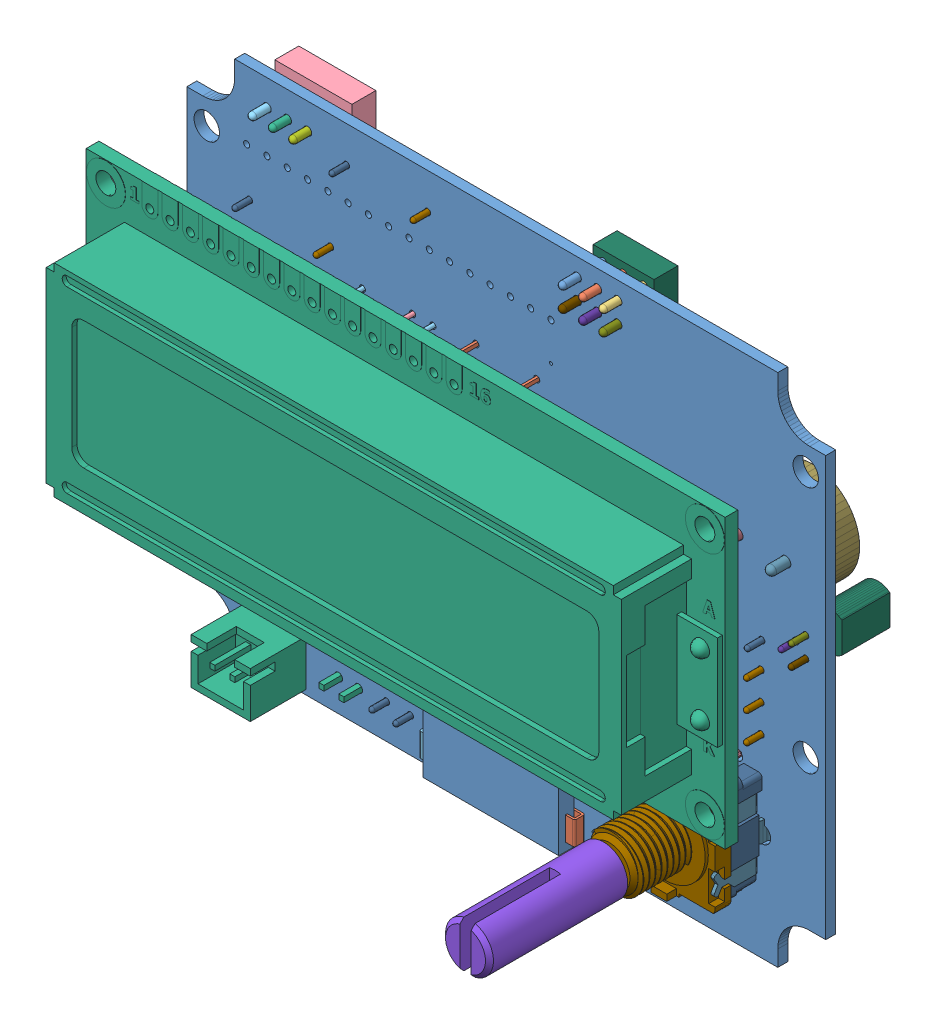
SolidWorks assembly margoulineur2000RevB_2, configuration Défaut. Lengths in mm.
Overall size (81.34 64.5 46.05).
210 component instances, 74 part files, 0 mates.
Components (placement in the parent):
- Layer_1-1: Layer_1 [Défaut] at origin size (80 64.5 1.25)
- U3-1: U3 [Défaut] at (36.2 -50.82 -0.625) x (0 1 0) z (0 0 -1) size (35.56 7.92 7.75)
  - Open CASCADE STEP translator 6.8 1.2.1-1: Open CASCADE STEP translator 6.8 1.2.1 [Défaut] at origin size (35.56 7.92 7.75)
    - Body_1-1: Body_1 [Défaut] at (16.5 3.8 0) x (0 1 0) z (1 0 0) size (7.92 7.75 35.56)
- C7-1: C7 [Défaut] at (28.275 -18.503 -0.625) x (1 0 0) z (0 0 -1) size (4 2 7.75)
  - Open CASCADE STEP translator 6.8 1.3.1-1: Open CASCADE STEP translator 6.8 1.3.1 [Défaut] at origin size (4 2 7.75)
    - Body_1_2-1: Body_1_2 [Défaut] at (1.27 -1.27 0) x (0 1 0) z (0 0 1) size (2 4 4)
    - Pin_1-1: Pin_1 [Défaut] x (0 -1 0) z (0 0 1) size (0.5 0.5 5.5)
    - Pin_2-1: Pin_2 [Défaut] at (2.54 2.54 0) x (0 -1 0) z (0 0 1) size (0.5 0.5 5.5)
- LCD1-1: LCD1 [Défaut] at (77.5 -11 0.625) size (80.25 36 12.9)
  - Open CASCADE STEP translator 6.8 1.4.1-1: Open CASCADE STEP translator 6.8 1.4.1 [Défaut] at origin size (80.25 36 12.9)
    - Body_1_3-1: Body_1_3 [Défaut] at (-37.5 -15.4 11) size (80.25 36 12.9)
- X1-1: X1 [Défaut] at (29.574 -28.08 -0.625) x (0 1 0) z (0 0 -1) size (11 4.5 15.2)
  - Open CASCADE STEP translator 6.8 1.5.1-1: Open CASCADE STEP translator 6.8 1.5.1 [Défaut] at origin size (11 4.5 15.2)
    - Body_1_4-1: Body_1_4 [Défaut] at (2.5 0 0) x (1 0 0) z (0 -1 0) size (11 15.2 4.5)
- C6-1: C6 [Défaut] at (28.267 -32.497 -0.625) x (1 0 0) z (0 0 -1) size (4 2 7.75)
  - Open CASCADE STEP translator 6.8 1.3.1-1: Open CASCADE STEP translator 6.8 1.3.1 [Défaut] at origin size (4 2 7.75)
    - Body_1_2-1: Body_1_2 [Défaut] at (1.27 -1.27 0) x (0 1 0) z (0 0 1) size (2 4 4)
    - Pin_1-1: Pin_1 [Défaut] x (0 -1 0) z (0 0 1) size (0.5 0.5 5.5)
    - Pin_2-1: Pin_2 [Défaut] at (2.54 2.54 0) x (0 -1 0) z (0 0 1) size (0.5 0.5 5.5)
- ENC1-1: ENC1 [Défaut] at (64 -46 0.625) size (13.1 15.13 35.07)
  - Open CASCADE STEP translator 6.8 1.7.1-1: Open CASCADE STEP translator 6.8 1.7.1 [Défaut] at origin size (13.1 15.13 35.07)
    - Body_1-1: Body_1 [Défaut] at (2.5 -6.5 0) x (-1 0 0) z (0 0 1) size (13.1 15.13 35.07)
      - Imported-1: Imported [Défaut] at (0 0 13.6) size (6 6 18)
      - Imported_2-1: Imported_2 [Défaut] at (0 0 3.443) size (11.7 13.8 9.4)
      - Imported_3-1: Imported_3 [Défaut] at (-0.85 -0.6436 6.5892) size (11.7 13.3 3.9)
      - Imported-2: Imported [Défaut] at (0 0 6.6326) size (13.1 14.95 9.45)
        - Imported_2-1: Imported_2 [Défaut] at (-2.5 7.575 -10.2243) x (0 -1 0) z (0 0 1) size (2.34 1.5 6.65)
          - SOLID-1: SOLID [Défaut] at origin size (0.6 1.5 0.15)
          - SOLID_2-1: SOLID_2 [Défaut] at origin size (2.15 1.5 6.65)
        - Imported_2-2: Imported_2 [Défaut] at (0 7.575 -10.2243) x (0 -1 0) z (0 0 1) size (2.34 1.5 6.65)
          - SOLID-1: SOLID [Défaut] at origin size (0.6 1.5 0.15)
          - SOLID_2-1: SOLID_2 [Défaut] at origin size (2.15 1.5 6.65)
        - Imported_2-3: Imported_2 [Défaut] at (2.5 7.575 -10.2243) x (0 -1 0) z (0 0 1) size (2.34 1.5 6.65)
          - SOLID-1: SOLID [Défaut] at origin size (0.6 1.5 0.15)
          - SOLID_2-1: SOLID_2 [Défaut] at origin size (2.15 1.5 6.65)
        - Imported_4-1: Imported_4 [Défaut] at (-2.5 -7.075 -10.2243) x (0 1 0) z (0 0 1) size (2.15 1.5 4.73)
        - Imported_4-2: Imported_4 [Défaut] at (2.5 -7.075 -10.2243) x (0 1 0) z (0 0 1) size (2.15 1.5 4.73)
        - Imported_5-1: Imported_5 [Défaut] at (-24.7094 3.8245 8.4125) size (13.1 9.9 9.18)
- ICSP1-1: ICSP1 [Défaut] at (53.975 -6.731 -0.625) x (-1 0 0) z (0 0 -1) size (7.62 5.08 8.46)
  - Open CASCADE STEP translator 6.8 1.8.1-1: Open CASCADE STEP translator 6.8 1.8.1 [Défaut] at origin size (7.62 5.08 8.46)
    - Body_1_5-1: Body_1_5 [Défaut] at origin size (7.62 5.08 3)
    - Pin_1_2-1: Pin_1_2 [Défaut] x (0 -1 0) z (0 0 1) size (0.92 0.92 7.42)
    - Pin_2_2-1: Pin_2_2 [Défaut] at (2.54 2.54 0) x (0 -1 0) z (0 0 1) size (0.92 0.92 7.42)
    - Pin_3-1: Pin_3 [Défaut] at (5.08 5.08 0) x (0 -1 0) z (0 0 1) size (0.92 0.92 7.42)
    - Pin_4-1: Pin_4 [Défaut] at (2.54 7.62 0) x (0 -1 0) z (0 0 1) size (0.92 0.92 7.42)
    - Pin_5-1: Pin_5 [Défaut] at (0 5.08 0) x (0 -1 0) z (0 0 1) size (0.92 0.92 7.42)
    - Pin_6-1: Pin_6 [Défaut] at (-2.54 2.54 0) x (0 -1 0) z (0 0 1) size (0.92 0.92 7.42)
- RV1-1: RV1 [Défaut] at (10.06 -5.24 -0.625) x (0 -1 0) z (0 0 -1) size (4.83 9.65 8.46)
  - Open CASCADE STEP translator 6.8 1.9.1-1: Open CASCADE STEP translator 6.8 1.9.1 [Défaut] at origin size (4.83 9.65 8.46)
    - Body_1_6-1: Body_1_6 [Défaut] at origin size (4.83 9.65 3)
    - Pin_1_3-1: Pin_1_3 [Défaut] x (0 -1 0) z (0 0 1) size (0.92 0.92 7.42)
    - Pin_2_3-1: Pin_2_3 [Défaut] at (2.54 -2.54 0) x (0 -1 0) z (0 0 1) size (0.92 0.92 7.42)
    - Pin_3_2-1: Pin_3_2 [Défaut] at (5.08 -5.08 0) x (0 -1 0) z (0 0 1) size (0.92 0.92 7.42)
- R8-1: R8 [Défaut] at (71.9 -42.26 -0.625) x (-1 0 0) z (0 0 -1) size (10.82 1.37 5.33)
  - Open CASCADE STEP translator 6.8 1.10.1-1: Open CASCADE STEP translator 6.8 1.10.1 [Défaut] at origin size (10.82 1.37 5.33)
    - Body_1_7-1: Body_1_7 [Défaut] at origin size (5.08 1.37 1.37)
    - Pin_1_4-1: Pin_1_4 [Défaut] at origin size (3.2 0.66 4.98)
    - Pin_2_4-1: Pin_2_4 [Défaut] at (20.32 0 0) x (-1 0 0) z (0 0 1) size (3.2 0.66 4.98)
- R7-1: R7 [Défaut] at (71.9 -35.26 -0.625) x (-1 0 0) z (0 0 -1) size (10.82 1.37 5.33)
  - Open CASCADE STEP translator 6.8 1.10.1-1: Open CASCADE STEP translator 6.8 1.10.1 [Défaut] at origin size (10.82 1.37 5.33)
    - Body_1_7-1: Body_1_7 [Défaut] at origin size (5.08 1.37 1.37)
    - Pin_1_4-1: Pin_1_4 [Défaut] at origin size (3.2 0.66 4.98)
    - Pin_2_4-1: Pin_2_4 [Défaut] at (20.32 0 0) x (-1 0 0) z (0 0 1) size (3.2 0.66 4.98)
- R6-1: R6 [Défaut] at (71.9 -38.76 -0.625) x (-1 0 0) z (0 0 -1) size (10.82 1.37 5.33)
  - Open CASCADE STEP translator 6.8 1.10.1-1: Open CASCADE STEP translator 6.8 1.10.1 [Défaut] at origin size (10.82 1.37 5.33)
    - Body_1_7-1: Body_1_7 [Défaut] at origin size (5.08 1.37 1.37)
    - Pin_1_4-1: Pin_1_4 [Défaut] at origin size (3.2 0.66 4.98)
    - Pin_2_4-1: Pin_2_4 [Défaut] at (20.32 0 0) x (-1 0 0) z (0 0 1) size (3.2 0.66 4.98)
- R4-1: R4 [Défaut] at (18.02 -16.34 -0.625) x (-1 0 0) z (0 0 -1) size (10.82 1.37 5.33)
  - Open CASCADE STEP translator 6.8 1.10.1-1: Open CASCADE STEP translator 6.8 1.10.1 [Défaut] at origin size (10.82 1.37 5.33)
    - Body_1_7-1: Body_1_7 [Défaut] at origin size (5.08 1.37 1.37)
    - Pin_1_4-1: Pin_1_4 [Défaut] at origin size (3.2 0.66 4.98)
    - Pin_2_4-1: Pin_2_4 [Défaut] at (20.32 0 0) x (-1 0 0) z (0 0 1) size (3.2 0.66 4.98)
- C8-1: C8 [Défaut] at (21.985 -21.44 -0.625) x (0 1 0) z (0 0 -1) size (4 2 7.75)
  - Open CASCADE STEP translator 6.8 1.3.1-1: Open CASCADE STEP translator 6.8 1.3.1 [Défaut] at origin size (4 2 7.75)
    - Body_1_2-1: Body_1_2 [Défaut] at (1.27 -1.27 0) x (0 1 0) z (0 0 1) size (2 4 4)
    - Pin_1-1: Pin_1 [Défaut] x (0 -1 0) z (0 0 1) size (0.5 0.5 5.5)
    - Pin_2-1: Pin_2 [Défaut] at (2.54 2.54 0) x (0 -1 0) z (0 0 1) size (0.5 0.5 5.5)
- U1-1: U1 [Défaut] at (18 -20.15 0.625) size (21 16 8.33)
  - Open CASCADE STEP translator 6.8 1.15.1-1: Open CASCADE STEP translator 6.8 1.15.1 [Défaut] at origin size (21 16 8.33)
    - Body_1_8-1: Body_1_8 [Défaut] at origin size (21 16 3)
    - Pin_1_5-1: Pin_1_5 [Défaut] x (0 -1 0) z (0 0 1) size (0.66 0.66 7.16)
    - Pin_2_5-1: Pin_2_5 [Défaut] at (2.54 -2.54 0) x (0 -1 0) z (0 0 1) size (0.66 0.66 7.16)
    - Pin_3_3-1: Pin_3_3 [Défaut] at (5.08 -5.08 0) x (0 -1 0) z (0 0 1) size (0.66 0.66 7.16)
    - Pin_4_2-1: Pin_4_2 [Défaut] at (7.62 -7.62 0) x (0 -1 0) z (0 0 1) size (0.66 0.66 7.16)
    - Pin_5_2-1: Pin_5_2 [Défaut] at (10.16 -10.16 0) x (0 -1 0) z (0 0 1) size (0.66 0.66 7.16)
    - Pin_6_2-1: Pin_6_2 [Défaut] at (12.7 -12.7 0) x (0 -1 0) z (0 0 1) size (0.66 0.66 7.16)
- U2-1: U2 [Défaut] at (12.1035 -47.905 -0.625) x (-1 0 0) z (0 0 -1) size (5.46 4.47 2.16)
  - Open CASCADE STEP translator 6.8 1.16.1-1: Open CASCADE STEP translator 6.8 1.16.1 [Défaut] at origin size (5.46 4.47 2.16)
    - Body_1_9-1: Body_1_9 [Défaut] at origin size (2.16 4.47 1.91)
    - Pin_1_6-1: Pin_1_6 [Défaut] at origin size (1.65 0.54 1.33)
    - Pin_2_6-1: Pin_2_6 [Défaut] at origin size (1.65 0.54 1.33)
    - Pin_3_4-1: Pin_3_4 [Défaut] at origin size (1.65 0.54 1.33)
    - Pin_4_3-1: Pin_4_3 [Défaut] at origin size (1.65 0.54 1.33)
    - Pin_5_3-1: Pin_5_3 [Défaut] at (5.207 -3.81 0) x (-1 0 0) z (0 0 1) size (1.65 0.54 1.33)
    - Pin_6_3-1: Pin_6_3 [Défaut] at (5.207 -1.27 0) x (-1 0 0) z (0 0 1) size (1.65 0.54 1.33)
    - Pin_7-1: Pin_7 [Défaut] at (5.207 1.27 0) x (-1 0 0) z (0 0 1) size (1.65 0.54 1.33)
    - Pin_8-1: Pin_8 [Défaut] at (5.207 3.81 0) x (-1 0 0) z (0 0 1) size (1.65 0.54 1.33)
- C1-1: C1 [Défaut] at (11 -42 -0.625) x (1 0 0) z (0 0 -1) size (4 2 7.75)
  - Open CASCADE STEP translator 6.8 1.3.1-1: Open CASCADE STEP translator 6.8 1.3.1 [Défaut] at origin size (4 2 7.75)
    - Body_1_2-1: Body_1_2 [Défaut] at (1.27 -1.27 0) x (0 1 0) z (0 0 1) size (2 4 4)
    - Pin_1-1: Pin_1 [Défaut] x (0 -1 0) z (0 0 1) size (0.5 0.5 5.5)
    - Pin_2-1: Pin_2 [Défaut] at (2.54 2.54 0) x (0 -1 0) z (0 0 1) size (0.5 0.5 5.5)
- C2-1: C2 [Défaut] at (19.9346 -40.5 -0.625) x (1 0 0) z (0 0 -1) size (4 2 7.75)
  - Open CASCADE STEP translator 6.8 1.3.1-1: Open CASCADE STEP translator 6.8 1.3.1 [Défaut] at origin size (4 2 7.75)
    - Body_1_2-1: Body_1_2 [Défaut] at (1.27 -1.27 0) x (0 1 0) z (0 0 1) size (2 4 4)
    - Pin_1-1: Pin_1 [Défaut] x (0 -1 0) z (0 0 1) size (0.5 0.5 5.5)
    - Pin_2-1: Pin_2 [Défaut] at (2.54 2.54 0) x (0 -1 0) z (0 0 1) size (0.5 0.5 5.5)
- C3-1: C3 [Défaut] at (10.5 -58.04 -0.625) x (0 1 0) z (0 0 -1) size (5.08 5.08 8.33)
  - Open CASCADE STEP translator 6.8 1.19.1-1: Open CASCADE STEP translator 6.8 1.19.1 [Défaut] at origin size (5.08 5.08 8.33)
    - Body_1_10-1: Body_1_10 [Défaut] at origin size (5.08 5.08 3)
    - Pin_1_7-1: Pin_1_7 [Défaut] x (0 -1 0) z (0 0 1) size (0.66 0.66 7.16)
    - Pin_2_7-1: Pin_2_7 [Défaut] at (2.54 2.54 0) x (0 -1 0) z (0 0 1) size (0.66 0.66 7.16)
- R5-1: R5 [Défaut] at (54.5 -64.5 -0.625) x (0 1 0) z (0 0 -1) size (10.82 1.37 5.33)
  - Open CASCADE STEP translator 6.8 1.10.1-1: Open CASCADE STEP translator 6.8 1.10.1 [Défaut] at origin size (10.82 1.37 5.33)
    - Body_1_7-1: Body_1_7 [Défaut] at origin size (5.08 1.37 1.37)
    - Pin_1_4-1: Pin_1_4 [Défaut] at origin size (3.2 0.66 4.98)
    - Pin_2_4-1: Pin_2_4 [Défaut] at (20.32 0 0) x (-1 0 0) z (0 0 1) size (3.2 0.66 4.98)
- R9-1: R9 [Défaut] at (57 -54.34 -0.625) x (0 -1 0) z (0 0 -1) size (10.82 1.37 5.33)
  - Open CASCADE STEP translator 6.8 1.10.1-1: Open CASCADE STEP translator 6.8 1.10.1 [Défaut] at origin size (10.82 1.37 5.33)
    - Body_1_7-1: Body_1_7 [Défaut] at origin size (5.08 1.37 1.37)
    - Pin_1_4-1: Pin_1_4 [Défaut] at origin size (3.2 0.66 4.98)
    - Pin_2_4-1: Pin_2_4 [Défaut] at (20.32 0 0) x (-1 0 0) z (0 0 1) size (3.2 0.66 4.98)
- R10-1: R10 [Défaut] at (7 -45 -0.625) x (0 -1 0) z (0 0 -1) size (10.82 1.37 5.33)
  - Open CASCADE STEP translator 6.8 1.10.1-1: Open CASCADE STEP translator 6.8 1.10.1 [Défaut] at origin size (10.82 1.37 5.33)
    - Body_1_7-1: Body_1_7 [Défaut] at origin size (5.08 1.37 1.37)
    - Pin_1_4-1: Pin_1_4 [Défaut] at origin size (3.2 0.66 4.98)
    - Pin_2_4-1: Pin_2_4 [Défaut] at (20.32 0 0) x (-1 0 0) z (0 0 1) size (3.2 0.66 4.98)
- R11-1: R11 [Défaut] at (4.5 -45 -0.625) x (0 -1 0) z (0 0 -1) size (10.82 1.37 5.33)
  - Open CASCADE STEP translator 6.8 1.10.1-1: Open CASCADE STEP translator 6.8 1.10.1 [Défaut] at origin size (10.82 1.37 5.33)
    - Body_1_7-1: Body_1_7 [Défaut] at origin size (5.08 1.37 1.37)
    - Pin_1_4-1: Pin_1_4 [Défaut] at origin size (3.2 0.66 4.98)
    - Pin_2_4-1: Pin_2_4 [Défaut] at (20.32 0 0) x (-1 0 0) z (0 0 1) size (3.2 0.66 4.98)
- BUZ1-1: BUZ1 [Défaut] at (69 -22 -0.625) x (-1 0 0) z (0 0 -1) size (12 12 8.59)
  - Open CASCADE STEP translator 6.8 1.24.1-1: Open CASCADE STEP translator 6.8 1.24.1 [Défaut] at origin size (12 12 8.59)
    - Body_1_11-1: Body_1_11 [Défaut] at origin size (12 12 3)
    - Pin_1_8-1: Pin_1_8 [Défaut] x (0 -1 0) z (0 0 1) size (1.17 1.17 7.67)
    - Pin_2_8-1: Pin_2_8 [Défaut] at (-6 -6 0) x (0 -1 0) z (0 0 1) size (1.17 1.17 7.67)
- Q1-1: Q1 [Défaut] at (77.5 -30 -0.625) x (0 -1 0) z (0 0 -1) size (4.85 3.81 11.33)
  - Open CASCADE STEP translator 6.8 1.25.1-1: Open CASCADE STEP translator 6.8 1.25.1 [Défaut] at origin size (4.85 3.81 11.33)
    - Body_1_12-1: Body_1_12 [Défaut] at origin size (4.85 3.81 6)
    - Pin_1_9-1: Pin_1_9 [Défaut] at (-1.27 -1.27 0) x (0 -1 0) z (0 0 1) size (0.66 0.66 8.66)
    - Pin_2_9-1: Pin_2_9 [Défaut] at (-1.27 1.27 0) x (0 -1 0) z (0 0 1) size (0.66 0.66 8.66)
    - Pin_3_5-1: Pin_3_5 [Défaut] at (1.27 1.27 0) x (0 -1 0) z (0 0 1) size (0.66 0.66 8.66)
- R12-1: R12 [Défaut] at (61.84 -32 -0.625) x (1 0 0) z (0 0 -1) size (10.82 1.37 5.33)
  - Open CASCADE STEP translator 6.8 1.10.1-1: Open CASCADE STEP translator 6.8 1.10.1 [Défaut] at origin size (10.82 1.37 5.33)
    - Body_1_7-1: Body_1_7 [Défaut] at origin size (5.08 1.37 1.37)
    - Pin_1_4-1: Pin_1_4 [Défaut] at origin size (3.2 0.66 4.98)
    - Pin_2_4-1: Pin_2_4 [Défaut] at (20.32 0 0) x (-1 0 0) z (0 0 1) size (3.2 0.66 4.98)
- M1-1: M1 [Défaut] at (32.215 -63.4058 0.625) x (-1 0 0) z (0 0 1) size (19.49 13 2.16)
  - Open CASCADE STEP translator 6.8 1.27.1-1: Open CASCADE STEP translator 6.8 1.27.1 [Défaut] at origin size (19.49 13 2.16)
    - Body_1_13-1: Body_1_13 [Défaut] at origin size (17 13 1.91)
    - Pin_1_10-1: Pin_1_10 [Défaut] at (-31.75 0 0) x (-1 0 0) z (0 0 1) size (3.61 2.95 1.33)
    - Pin_2_10-1: Pin_2_10 [Défaut] at (-31.75 -15.24 0) x (-1 0 0) z (0 0 1) size (3.61 2.95 1.33)
    - Pin_3_6-1: Pin_3_6 [Défaut] at origin size (3.61 2.95 1.33)
    - Pin_4_4-1: Pin_4_4 [Défaut] at origin size (3.61 2.95 1.33)
- R13-1: R13 [Défaut] at (30.16 -6.5 -0.625) x (-1 0 0) z (0 0 -1) size (10.82 1.37 5.33)
  - Open CASCADE STEP translator 6.8 1.10.1-1: Open CASCADE STEP translator 6.8 1.10.1 [Défaut] at origin size (10.82 1.37 5.33)
    - Body_1_7-1: Body_1_7 [Défaut] at origin size (5.08 1.37 1.37)
    - Pin_1_4-1: Pin_1_4 [Défaut] at origin size (3.2 0.66 4.98)
    - Pin_2_4-1: Pin_2_4 [Défaut] at (20.32 0 0) x (-1 0 0) z (0 0 1) size (3.2 0.66 4.98)
- BAT-1: BAT [Défaut] at (12.5 -62.5 0.625) size (7.4 5.75 10.4)
  - Open CASCADE STEP translator 6.8 1.29.1-1: Open CASCADE STEP translator 6.8 1.29.1 [Défaut] at origin size (7.4 5.75 10.4)
    - Body_1_14-1: Body_1_14 [Défaut] at (-1.25 -0.5 0) x (-1 0 0) z (0 1 0) size (7.4 10.4 5.75)
- SWITCH-1: SWITCH [Défaut] at (19 -62.5 -0.625) x (-1 0 0) z (0 0 -1) size (7.4 5.75 10.4)
  - Open CASCADE STEP translator 6.8 1.30.1-1: Open CASCADE STEP translator 6.8 1.30.1 [Défaut] at origin size (7.4 5.75 10.4)
    - Body_1_14-1: Body_1_14 [Défaut] at (-1.25 -0.5 0) x (-1 0 0) z (0 1 0) size (7.4 10.4 5.75)
- U4-1: U4 [Défaut] at (20.9746 -44.201 -0.625) x (-1 0 0) z (0 0 -1) size (2.51 2.51 0.76)
  - Open CASCADE STEP translator 6.8 1.31.1-1: Open CASCADE STEP translator 6.8 1.31.1 [Défaut] at origin size (2.51 2.51 0.76)
    - Body_1_15-1: Body_1_15 [Défaut] at origin size (2.51 1.3 0.71)
    - Pin_1_11-1: Pin_1_11 [Défaut] at (-2.1844 -0.254 0) x (0 1 0) z (0 0 1) size (0.63 0.25 0.47)
    - Pin_2_11-1: Pin_2_11 [Défaut] at (-1.2446 -1.1938 0) x (0 1 0) z (0 0 1) size (0.63 0.25 0.47)
    - Pin_3_7-1: Pin_3_7 [Défaut] at (-0.2794 -2.159 0) x (0 1 0) z (0 0 1) size (0.63 0.25 0.47)
    - Pin_4_5-1: Pin_4_5 [Défaut] at (-0.2267 2.1106 0) x (-0.002065 -0.999998 0) z (0 0 1) size (0.59 0.25 0.47)
    - Pin_5_4-1: Pin_5_4 [Défaut] at (-1.1684 1.1708 0) x (-0.002073 -0.999998 0) z (0 0 1) size (0.58 0.25 0.47)
    - Pin_6_4-1: Pin_6_4 [Défaut] at (-2.1356 0.2056 0) x (-0.002061 -0.999998 0) z (0 0 1) size (0.58 0.25 0.47)
- U5-1: U5 [Défaut] at (20.9746 -49.201 -0.625) x (-1 0 0) z (0 0 -1) size (2.51 2.51 0.76)
  - Open CASCADE STEP translator 6.8 1.31.1-1: Open CASCADE STEP translator 6.8 1.31.1 [Défaut] at origin size (2.51 2.51 0.76)
    - Body_1_15-1: Body_1_15 [Défaut] at origin size (2.51 1.3 0.71)
    - Pin_1_11-1: Pin_1_11 [Défaut] at (-2.1844 -0.254 0) x (0 1 0) z (0 0 1) size (0.63 0.25 0.47)
    - Pin_2_11-1: Pin_2_11 [Défaut] at (-1.2446 -1.1938 0) x (0 1 0) z (0 0 1) size (0.63 0.25 0.47)
    - Pin_3_7-1: Pin_3_7 [Défaut] at (-0.2794 -2.159 0) x (0 1 0) z (0 0 1) size (0.63 0.25 0.47)
    - Pin_4_5-1: Pin_4_5 [Défaut] at (-0.2267 2.1106 0) x (-0.002065 -0.999998 0) z (0 0 1) size (0.59 0.25 0.47)
    - Pin_5_4-1: Pin_5_4 [Défaut] at (-1.1684 1.1708 0) x (-0.002073 -0.999998 0) z (0 0 1) size (0.58 0.25 0.47)
    - Pin_6_4-1: Pin_6_4 [Défaut] at (-2.1356 0.2056 0) x (-0.002061 -0.999998 0) z (0 0 1) size (0.58 0.25 0.47)
- R1-1: R1 [Défaut] at (17.5 -45 -0.625) x (0 -1 0) z (0 0 -1) size (10.82 1.37 5.33)
  - Open CASCADE STEP translator 6.8 1.10.1-1: Open CASCADE STEP translator 6.8 1.10.1 [Défaut] at origin size (10.82 1.37 5.33)
    - Body_1_7-1: Body_1_7 [Défaut] at origin size (5.08 1.37 1.37)
    - Pin_1_4-1: Pin_1_4 [Défaut] at origin size (3.2 0.66 4.98)
    - Pin_2_4-1: Pin_2_4 [Défaut] at (20.32 0 0) x (-1 0 0) z (0 0 1) size (3.2 0.66 4.98)
- M2-1: M2 [Défaut] at (54.064 -21 -0.625) x (-1 0 0) z (0 0 -1) size (43 40 9.6)
  - Open CASCADE STEP translator 6.8 1.34.1-1: Open CASCADE STEP translator 6.8 1.34.1 [Défaut] at origin size (43 40 9.6)
    - Body_1_16-1: Body_1_16 [Défaut] at origin size (43 40 3)
    - Pin_1_12-1: Pin_1_12 [Défaut] at (7.754 -9.626 0) x (0 -1 0) z (0 0 1) size (0.66 0.66 7.16)
    - Pin_2_12-1: Pin_2_12 [Défaut] at (10.294 -12.166 0) x (0 -1 0) z (0 0 1) size (0.66 0.66 7.16)
    - Pin_3_8-1: Pin_3_8 [Défaut] at (12.834 -14.706 0) x (0 -1 0) z (0 0 1) size (0.66 0.66 7.16)
    - Pin_4_6-1: Pin_4_6 [Défaut] at (15.374 -17.246 0) x (0 -1 0) z (0 0 1) size (0.66 0.66 7.16)
    - Pin_5_5-1: Pin_5_5 [Défaut] at (53 3 0) x (0 -1 0) z (0 0 1) size (3.1 3.1 9.6)
    - Pin_6_5-1: Pin_6_5 [Défaut] x (0 -1 0) z (0 0 1) size (3.1 3.1 9.6)
- R2-1: R2 [Défaut] at (25 -52 -0.625) x (0 -1 0) z (0 0 -1) size (10.82 1.37 5.33)
  - Open CASCADE STEP translator 6.8 1.10.1-1: Open CASCADE STEP translator 6.8 1.10.1 [Défaut] at origin size (10.82 1.37 5.33)
    - Body_1_7-1: Body_1_7 [Défaut] at origin size (5.08 1.37 1.37)
    - Pin_1_4-1: Pin_1_4 [Défaut] at origin size (3.2 0.66 4.98)
    - Pin_2_4-1: Pin_2_4 [Défaut] at (20.32 0 0) x (-1 0 0) z (0 0 1) size (3.2 0.66 4.98)
- R3-1: R3 [Défaut] at (28 -52 -0.625) x (0 -1 0) z (0 0 -1) size (10.82 1.37 5.33)
  - Open CASCADE STEP translator 6.8 1.10.1-1: Open CASCADE STEP translator 6.8 1.10.1 [Défaut] at origin size (10.82 1.37 5.33)
    - Body_1_7-1: Body_1_7 [Défaut] at origin size (5.08 1.37 1.37)
    - Pin_1_4-1: Pin_1_4 [Défaut] at origin size (3.2 0.66 4.98)
    - Pin_2_4-1: Pin_2_4 [Défaut] at (20.32 0 0) x (-1 0 0) z (0 0 1) size (3.2 0.66 4.98)
